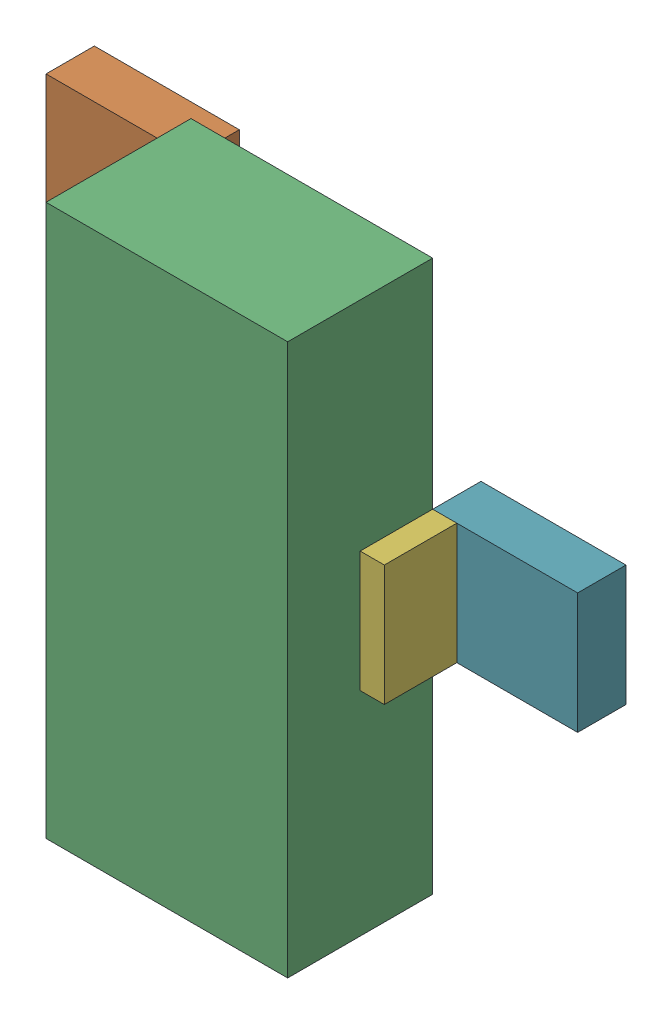
SolidWorks assembly Q4, configuration Default. Lengths in mm.
Overall size (2.79 2.9 1.02).
14 component instances, 3 part files, 0 mates.
Components (placement in the parent):
- 898052496-1: 898052496 [Default] at (32.2834 12.5831 0) size (0.76 0.64 0.25)
  - Extruded_10-1: Extruded_10 [Default] at origin size (0.76 0.64 0.25)
- 898052496-2: 898052496 [Default] at (32.2834 14.4881 0) size (0.76 0.64 0.25)
  - Extruded_10-1: Extruded_10 [Default] at origin size (0.76 0.64 0.25)
- 898052360-1: 898052360 [Default] at (33.2994 13.5356 0.254) size (1.27 2.9 0.76)
  - Extruded_11-1: Extruded_11 [Default] at origin size (1.27 2.9 0.76)
- 898052632-1: 898052632 [Default] at (32.6009 12.5831 0.254) size (0.13 0.64 0.38)
  - Extruded_12-1: Extruded_12 [Default] at origin size (0.13 0.64 0.38)
- 898052632-2: 898052632 [Default] at (32.6009 14.4881 0.254) size (0.13 0.64 0.38)
  - Extruded_12-1: Extruded_12 [Default] at origin size (0.13 0.64 0.38)
- 898052632-3: 898052632 [Default] at (33.9979 13.5229 0.254) size (0.13 0.64 0.38)
  - Extruded_12-1: Extruded_12 [Default] at origin size (0.13 0.64 0.38)
- 898052496-3: 898052496 [Default] at (34.3154 13.5229 0) size (0.76 0.64 0.25)
  - Extruded_10-1: Extruded_10 [Default] at origin size (0.76 0.64 0.25)
